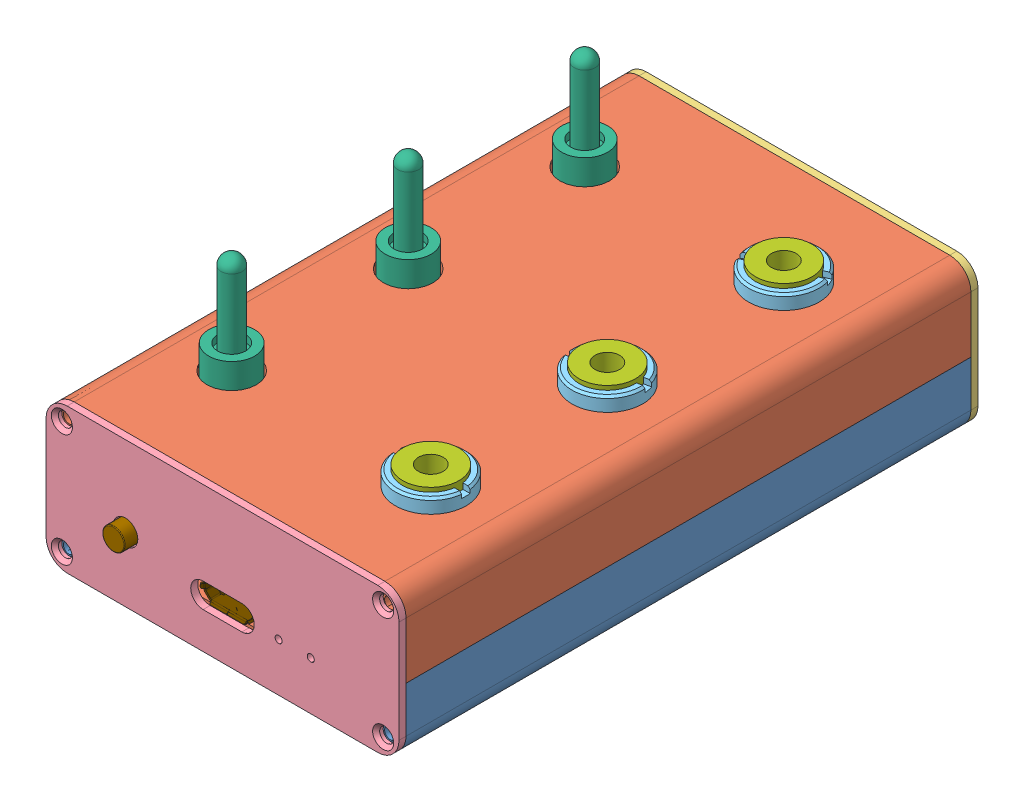
SolidWorks assembly case-full, configuration Default. Lengths in mm.
Overall size (82.81 95.61 103.19).
108 component instances, 20 part files, 23 mates.
Components (placement in the parent):
- case-1: case [Default] at (-9.9049 -10.2865 -40) size (50 11 80)
- top-case-2: top-case [Default] at (1.6835 8.41 -40) x (-1 0 0) z (0 0 1) size (50 11 80)
- case-lid-1: case-lid [Default] at (-11.7051 -0.4225 -41) size (50 20.5 1)
- case-lid-usb-1: case-lid-usb [Default] at (-11.7051 -0.4225 40) size (50 20.5 1)
- ringM8-1: ringM8 [Default] at (9.3893 9.3118 25) x (1 0 0) z (0 1 0) size (10 10 2)
- ringM8-2: ringM8 [Default] at (9.3893 9.3118 0) x (0.982082 0 -0.188455) z (0 1 0) size (10 10 2)
- ringM8-3: ringM8 [Default] at (9.3893 9.3118 -25) x (0.918365 0 -0.395734) z (0 1 0) size (10 10 2)
- PCB-assembly_v1.1-1: PCB-assembly_v1.1 [Default] at (67.1534 66.9625 123.4804) x (-0.337053 0.880168 0.334215) z (-0.925245 -0.375317 0.055309) size (64.17 83.92 50.34)
  - toggle-switch-4: toggle-switch [Default] at (-67.9927 86.0354 100.4663) x (0.334215 -0.940873 0.055309) z (0.337053 0.174117 0.925245) size (6.9 31.5 13.2)
  - 3,5mmjack_MultiComp-1: 3,5mmjack_MultiComp [Default] at (-77.3391 81.8383 75.298) x (-0.334215 0.940873 -0.055309) z (0.880168 0.290588 -0.375317) size (9 10.5 21.9)
  - ledTruckv1.1_new-1: ledTruckv1.1_new [Default] at (-61.225 73.4972 110.8928) x (-0.334215 0.940873 -0.055309) z (0.880168 0.290588 -0.375317) size (82.71 47 11)
    - R_0603_1608Metric-1: R_0603_1608Metric [Default] at (8.89 -22.225 1.65) x (-1 0 0) z (0 0 1) size (1.6 0.8 0.45)
      - SOLID-0-1: SOLID-0 [Default] at origin size (1.6 0.8 0.45) (hidden)
    - R_0603_1608Metric-2: R_0603_1608Metric [Default] at (8.89 -24.003 1.65) size (1.6 0.8 0.45)
      - SOLID-0-1: SOLID-0 [Default] at origin size (1.6 0.8 0.45) (hidden)
    - SW_Tactile_SPST_Angled_PTS645Vx58-2LFS-1: SW_Tactile_SPST_Angled_PTS645Vx58-2LFS [Default] at (3 -12 1.65) x (0 1 0) z (0 0 1) size (7.4 9.9 11)
      - SOLID-1-1: SOLID-1 [Default] at origin size (7.4 9.9 11)
    - R_0603_1608Metric-3: R_0603_1608Metric [Default] at (26.416 -8.636 1.65) x (-1 0 0) z (0 0 1) size (1.6 0.8 0.45)
      - SOLID-0-1: SOLID-0 [Default] at origin size (1.6 0.8 0.45) (hidden)
    - R_0603_1608Metric-4: R_0603_1608Metric [Default] at (21.082 -14.478 1.65) size (1.6 0.8 0.45)
      - SOLID-0-1: SOLID-0 [Default] at origin size (1.6 0.8 0.45) (hidden)
    - R_0603_1608Metric-5: R_0603_1608Metric [Default] at (21.082 -8.636 1.65) x (-1 0 0) z (0 0 1) size (1.6 0.8 0.45)
      - SOLID-0-1: SOLID-0 [Default] at origin size (1.6 0.8 0.45) (hidden)
    - R_0603_1608Metric-6: R_0603_1608Metric [Default] at (27.686 -35.052 1.65) x (-1 0 0) z (0 0 1) size (1.6 0.8 0.45)
      - SOLID-0-1: SOLID-0 [Default] at origin size (1.6 0.8 0.45) (hidden)
    - SOT-23-1: SOT-23 [Default] at (21.082 -4.572 1.65) x (0 -1 0) z (0 0 1) size (2.5 3 1.2)
      - SOLID-2-1: SOLID-2 [Default] at origin size (2.5 3 1.2)
    - SOT-23-2: SOT-23 [Default] at (31.496 -33.782 1.65) x (-1 0 0) z (0 0 1) size (2.5 3 1.2)
      - SOLID-2-1: SOLID-2 [Default] at origin size (2.5 3 1.2)
    - SOT-23-3: SOT-23 [Default] at (23.876 -33.782 1.65) size (2.5 3 1.2)
      - SOLID-2-1: SOLID-2 [Default] at origin size (2.5 3 1.2)
    - D_SOD-323-1: D_SOD-323 [Default] at (21.082 -11.684 1.65) size (2.5 1.25 1.1)
      - SOLID-3-1: SOLID-3 [Default] at origin size (2.5 1.25 1.1)
    - C_0603_1608Metric-1: C_0603_1608Metric [Default] at (3.81 -3.556 1.65) size (1.6 0.8 0.8)
      - SOLID-4-1: SOLID-4 [Default] at origin size (1.6 0.8 0.8) (hidden)
    - R_0603_1608Metric-7: R_0603_1608Metric [Default] at (51.938 -2.799 1.65) size (1.6 0.8 0.45)
      - SOLID-0-1: SOLID-0 [Default] at origin size (1.6 0.8 0.45) (hidden)
    - SOT-23-4: SOT-23 [Default] at (57.78 -3.688 1.65) x (0 -1 0) z (0 0 1) size (2.5 3 1.2)
      - SOLID-2-1: SOLID-2 [Default] at origin size (2.5 3 1.2)
    - C_0603_1608Metric-2: C_0603_1608Metric [Default] at (51.938 -4.45 1.65) x (-1 0 0) z (0 0 1) size (1.6 0.8 0.8)
      - SOLID-4-1: SOLID-4 [Default] at origin size (1.6 0.8 0.8) (hidden)
    - SOT-23-5-1: SOT-23-5 [Default] at (32.126 -4.704 1.65) x (0 -1 0) z (0 0 1) size (2.8 2.9 1.55)
      - SOLID-5-1: SOLID-5 [Default] at origin size (2.8 2.9 1.55)
    - SOT-23-5-2: SOT-23-5 [Default] at (26.416 -4.699 1.65) x (0 -1 0) z (0 0 1) size (2.8 2.9 1.55)
      - SOLID-5-1: SOLID-5 [Default] at origin size (2.8 2.9 1.55)
    - JST_PH_S2B-PH-K_1x02_P2.00mm_Horizontal-1: JST_PH_S2B-PH-K_1x02_P2.00mm_Horizontal [Default] at (74.544 -6.228 1.65) size (5.9 7.6 8.25)
      - SOLID-6-1: SOLID-6 [Default] at origin size (5.9 7.6 8.25)
    - R_0603_1608Metric-8: R_0603_1608Metric [Default] at (57.1958 -32.8676 1.65) x (-1 0 0) z (0 0 1) size (1.6 0.8 0.45)
      - SOLID-0-1: SOLID-0 [Default] at origin size (1.6 0.8 0.45) (hidden)
    - R_0603_1608Metric-9: R_0603_1608Metric [Default] at (57.526 -8.006 1.65) size (1.6 0.8 0.45)
      - SOLID-0-1: SOLID-0 [Default] at origin size (1.6 0.8 0.45) (hidden)
    - R_0603_1608Metric-10: R_0603_1608Metric [Default] at (57.526 -6.355 1.65) x (-1 0 0) z (0 0 1) size (1.6 0.8 0.45)
      - SOLID-0-1: SOLID-0 [Default] at origin size (1.6 0.8 0.45) (hidden)
    - R_0603_1608Metric-11: R_0603_1608Metric [Default] at (5.969 -36.068 1.65) x (0 -1 0) z (0 0 1) size (1.6 0.8 0.45)
      - SOLID-0-1: SOLID-0 [Default] at origin size (1.6 0.8 0.45) (hidden)
    - R_0603_1608Metric-12: R_0603_1608Metric [Default] at (5.9944 -31.4706 1.65) x (0 1 0) z (0 0 1) size (1.6 0.8 0.45)
      - SOLID-0-1: SOLID-0 [Default] at origin size (1.6 0.8 0.45) (hidden)
    - R_0603_1608Metric-13: R_0603_1608Metric [Default] at (46.604 -7.752 1.65) size (1.6 0.8 0.45)
      - SOLID-0-1: SOLID-0 [Default] at origin size (1.6 0.8 0.45) (hidden)
    - R_0603_1608Metric-14: R_0603_1608Metric [Default] at (59.812 -12.705 1.65) x (0 1 0) z (0 0 1) size (1.6 0.8 0.45)
      - SOLID-0-1: SOLID-0 [Default] at origin size (1.6 0.8 0.45) (hidden)
    - R_0603_1608Metric-15: R_0603_1608Metric [Default] at (32.1514 -8.636 1.65) x (-1 0 0) z (0 0 1) size (1.6 0.8 0.45)
      - SOLID-0-1: SOLID-0 [Default] at origin size (1.6 0.8 0.45) (hidden)
    - R_0603_1608Metric-16: R_0603_1608Metric [Default] at (51.938 -38.994 1.65) x (-1 0 0) z (0 0 1) size (1.6 0.8 0.45)
      - SOLID-0-1: SOLID-0 [Default] at origin size (1.6 0.8 0.45) (hidden)
    - R_0603_1608Metric-17: R_0603_1608Metric [Default] at (51.938 -34.93 1.65) size (1.6 0.8 0.45)
      - SOLID-0-1: SOLID-0 [Default] at origin size (1.6 0.8 0.45) (hidden)
    - R_0603_1608Metric-18: R_0603_1608Metric [Default] at (27.686 -36.957 1.65) size (1.6 0.8 0.45)
      - SOLID-0-1: SOLID-0 [Default] at origin size (1.6 0.8 0.45) (hidden)
    - R_0603_1608Metric-19: R_0603_1608Metric [Default] at (51.938 -36.962 1.65) x (-1 0 0) z (0 0 1) size (1.6 0.8 0.45)
      - SOLID-0-1: SOLID-0 [Default] at origin size (1.6 0.8 0.45) (hidden)
    - R_0603_1608Metric-20: R_0603_1608Metric [Default] at (51.9176 -32.9184 1.65) x (-1 0 0) z (0 0 1) size (1.6 0.8 0.45)
      - SOLID-0-1: SOLID-0 [Default] at origin size (1.6 0.8 0.45) (hidden)
    - R_0603_1608Metric-21: R_0603_1608Metric [Default] at (27.686 -38.862 1.65) size (1.6 0.8 0.45)
      - SOLID-0-1: SOLID-0 [Default] at origin size (1.6 0.8 0.45) (hidden)
    - C_0805_2012Metric-1: C_0805_2012Metric [Default] at (26.416 -14.478 1.65) x (-1 0 0) z (0 0 1) size (2 1.25 1.25)
      - SOLID-7-1: SOLID-7 [Default] at origin size (2 1.25 1.25)
    - C_0603_1608Metric-3: C_0603_1608Metric [Default] at (46.604 -6.101 1.65) x (-1 0 0) z (0 0 1) size (1.6 0.8 0.8)
      - SOLID-4-1: SOLID-4 [Default] at origin size (1.6 0.8 0.8) (hidden)
    - C_0805_2012Metric-2: C_0805_2012Metric [Default] at (32.126 -11.689 1.65) size (2 1.25 1.25)
      - SOLID-7-1: SOLID-7 [Default] at origin size (2 1.25 1.25)
    - C_0603_1608Metric-4: C_0603_1608Metric [Default] at (46.604 -4.45 1.65) size (1.6 0.8 0.8)
      - SOLID-4-1: SOLID-4 [Default] at origin size (1.6 0.8 0.8) (hidden)
    - C_0603_1608Metric-5: C_0603_1608Metric [Default] at (46.604 -2.799 1.65) size (1.6 0.8 0.8)
      - SOLID-4-1: SOLID-4 [Default] at origin size (1.6 0.8 0.8) (hidden)
    - C_0805_2012Metric-3: C_0805_2012Metric [Default] at (26.416 -11.684 1.65) x (-1 0 0) z (0 0 1) size (2 1.25 1.25)
      - SOLID-7-1: SOLID-7 [Default] at origin size (2 1.25 1.25)
    - C_0603_1608Metric-6: C_0603_1608Metric [Default] at (57.526 -9.657 1.65) size (1.6 0.8 0.8)
      - SOLID-4-1: SOLID-4 [Default] at origin size (1.6 0.8 0.8) (hidden)
    - C_0603_1608Metric-7: C_0603_1608Metric [Default] at (57.526 -15.626 1.65) size (1.6 0.8 0.8)
      - SOLID-4-1: SOLID-4 [Default] at origin size (1.6 0.8 0.8) (hidden)
    - C_0805_2012Metric-4: C_0805_2012Metric [Default] at (32.126 -14.478 1.65) size (2 1.25 1.25)
      - SOLID-7-1: SOLID-7 [Default] at origin size (2 1.25 1.25)
    - LED_0805_2012Metric-1: LED_0805_2012Metric [Default] at (2.6589 -36 1.65) x (0 -1 0) z (0 0 1) size (2 1.25 1.1)
      - SOLID-8-1: SOLID-8 [Default] at origin size (2 1.25 1.1)
    - LED_0805_2012Metric-2: LED_0805_2012Metric [Default] at (2.6589 -31.45 1.65) x (0 -1 0) z (0 0 1) size (2 1.25 1.1)
      - SOLID-8-1: SOLID-8 [Default] at origin size (2 1.25 1.1)
    - QFN-32-1EP_4x4mm_P0.4mm_EP2.65x2.65mm-1: QFN-32-1EP_4x4mm_P0.4mm_EP2.65x2.65mm [Default] at (49.136 -12.5 1.65) x (-1 0 0) z (0 0 1) size (4 4 0.92)
      - SOLID-9-1: SOLID-9 [Default] at origin size (4 4 0.92)
    - USB_Micro-B_Molex_47346-0001-1: USB_Micro-B_Molex_47346-0001 [Default] at (3.3873 -23.4924 1.65) x (0 -1 0) z (0 0 1) size (7.98 5.42 2.94)
      - SOLID-10-1: SOLID-10 [Default] at origin size (7.98 5.42 2.94)
    - Crystal_SMD_0603-4Pin_6.0x3.5mm-1: Crystal_SMD_0603-4Pin_6.0x3.5mm [Default] at (57.526 -12.705 1.65) x (0 1 0) z (0 0 1) size (6 3.5 1.03)
      - SOLID-11-1: SOLID-11 [Default] at origin size (6 3.5 1.03) (hidden)
    - COMPOUND-1: COMPOUND [Default] at origin size (80 47 1.6)
  - toggle-switch-5: toggle-switch [Default] at (-76.348 109.5572 99.0835) x (0.334215 -0.940873 0.055309) z (0.337053 0.174117 0.925245) size (6.9 31.5 13.2)
  - toggle-switch-6: toggle-switch [Default] at (-84.7034 133.079 97.7008) x (0.334215 -0.940873 0.055309) z (0.337053 0.174117 0.925245) size (6.9 31.5 13.2)
  - 3,5mmjack_MultiComp-6: 3,5mmjack_MultiComp [Default] at (-85.6945 105.3601 73.9153) x (-0.334215 0.940873 -0.055309) z (0.880168 0.290588 -0.375317) size (9 10.5 21.9)
  - 3,5mmjack_MultiComp-7: 3,5mmjack_MultiComp [Default] at (-94.0499 128.882 72.5326) x (-0.334215 0.940873 -0.055309) z (0.880168 0.290588 -0.375317) size (9 10.5 21.9)
Mates (geometry in assembly coordinates):
- Coincident1: coincident aligned: plane of case-1 through (-27.6107 -2.4882 40) normal (1 0 0); plane of top-case-2 through (-27.6107 2.6118 40) normal (1 0 0)
- Coincident3: coincident aligned: plane of case-1 through (-27.6107 -2.4882 40) normal (1 0 0); plane of top-case-2 through (-27.6107 2.6118 40) normal (1 0 0)
- Parallel2: parallel aligned: plane of case-1 through (19.3893 -4.4882 40) normal (-1 0 0); plane of top-case-2 through (19.3893 0.6118 40) normal (-1 0 0)
- Coincident6: coincident anti-aligned: plane of case-1 through (19.8933 -1.6882 40) normal (0 1 0); plane of top-case-2 through (20.8893 -1.6882 40) normal (0 -1 0)
- Coincident7: coincident aligned: plane of case-1 through (-26.1107 -8.1882 40) normal (0 0 1); plane of top-case-2 through (17.8893 6.3118 40) normal (0 0 1)
- Coincident9: coincident anti-aligned: plane of case-1 through (-27.6107 -5.4882 40) normal (1 0 0); plane of PCB-assembly-1/ledTruck_PCB.step-1/ledTruck.step-1/COMPOUND.step-1 through (-27.6107 -7.0882 40) normal (-1 0 0)
- Coincident10: coincident anti-aligned: plane of case-1 through (19.3893 -5.4882 40) normal (0 -1 0); plane of PCB-assembly-1/ledTruck_PCB.step-1/ledTruck.step-1/COMPOUND.step-1 through (-4.1107 -5.4882 0) normal (0 1 0)
- Coincident11: coincident aligned: plane of case-1 through (-26.1107 -8.1882 40) normal (0 0 1); plane of PCB-assembly-1/ledTruck_PCB.step-1/ledTruck.step-1/COMPOUND.step-1 through (19.3893 -7.0882 40) normal (0 0 1)
- Coincident12: coincident anti-aligned: plane of top-case-2 through (17.8893 6.3118 -40) normal (0 0 -1); plane of case-lid-1 through (17.8893 6.3118 -40) normal (0 0 1)
- Coincident13: coincident aligned: plane of top-case-2 through (17.8893 9.3118 40) normal (0 1 0); plane of case-lid-1 through (-26.1107 9.3118 -40) normal (0 1 0)
- Coincident14: coincident aligned: plane of case-1 through (-29.1107 -0.1882 40) normal (-1 0 0); plane of case-lid-1 through (-29.1107 6.3118 -40) normal (-1 0 0)
- Coincident15: coincident anti-aligned: plane of top-case-2 through (17.8893 6.3118 40) normal (0 0 1); plane of case-lid-usb-1 through (17.8893 6.3118 40) normal (0 0 -1)
- Coincident16: coincident aligned: plane of top-case-2 through (17.8893 9.3118 40) normal (0 1 0); plane of case-lid-usb-1 through (-26.1107 9.3118 41) normal (0 1 0)
- Coincident18: coincident aligned: plane of top-case-2 through (-29.1107 6.3118 40) normal (-1 0 0); plane of case-lid-usb-1 through (-29.1107 6.3118 41) normal (-1 0 0)
- Coincident19: coincident anti-aligned: plane of top-case-2 through (17.8893 9.3118 40) normal (0 1 0); plane of ringM8-1 through (9.3893 9.3118 25) normal (0 -1 0)
- Concentric1: concentric anti-aligned: cylinder of PCB-assembly-1/3,5mmjack_MultiComp-1 through (9.3893 28.9343 25) axis (0 -1 0) radius 4; circle of ringM8-1
- Coincident20: coincident anti-aligned: plane of top-case-2 through (17.8893 9.3118 40) normal (0 1 0); plane of ringM8-2 through (9.3893 9.3118 0) normal (0 -1 0)
- Concentric2: concentric anti-aligned: cylinder of PCB-assembly-1/3,5mmjack_MultiComp-4 through (9.3893 12.0118 0) axis (0 -1 0) radius 4; circle of ringM8-2
- Coincident21: coincident anti-aligned: plane of top-case-2 through (17.8893 9.3118 40) normal (0 1 0); plane of ringM8-3 through (9.3893 9.3118 -25) normal (0 -1 0)
- Concentric3: concentric anti-aligned: cylinder of PCB-assembly-1/3,5mmjack_MultiComp-5 through (9.3893 12.0118 -25) axis (0 -1 0) radius 4; circle of ringM8-3
- Coincident22: coincident anti-aligned: plane of case-1 through (-27.6107 -5.4882 40) normal (1 0 0); plane of PCB-assembly_v1.1-1/ledTruckv1.1_new-1/COMPOUND-1 through (-27.6107 -7.1882 40) normal (-1 0 0)
- Coincident23: coincident anti-aligned: plane of case-1 through (-26.4107 -7.1882 40) normal (0 1 0); plane of PCB-assembly_v1.1-1/ledTruckv1.1_new-1/COMPOUND-1 through (-4.1107 -7.1882 0) normal (0 -1 0)
- Coincident24: coincident aligned: plane of case-1 through (-26.1107 -8.1882 40) normal (0 0 1); plane of PCB-assembly_v1.1-1/ledTruckv1.1_new-1/COMPOUND-1 through (19.3893 -7.1882 40) normal (0 0 1)
